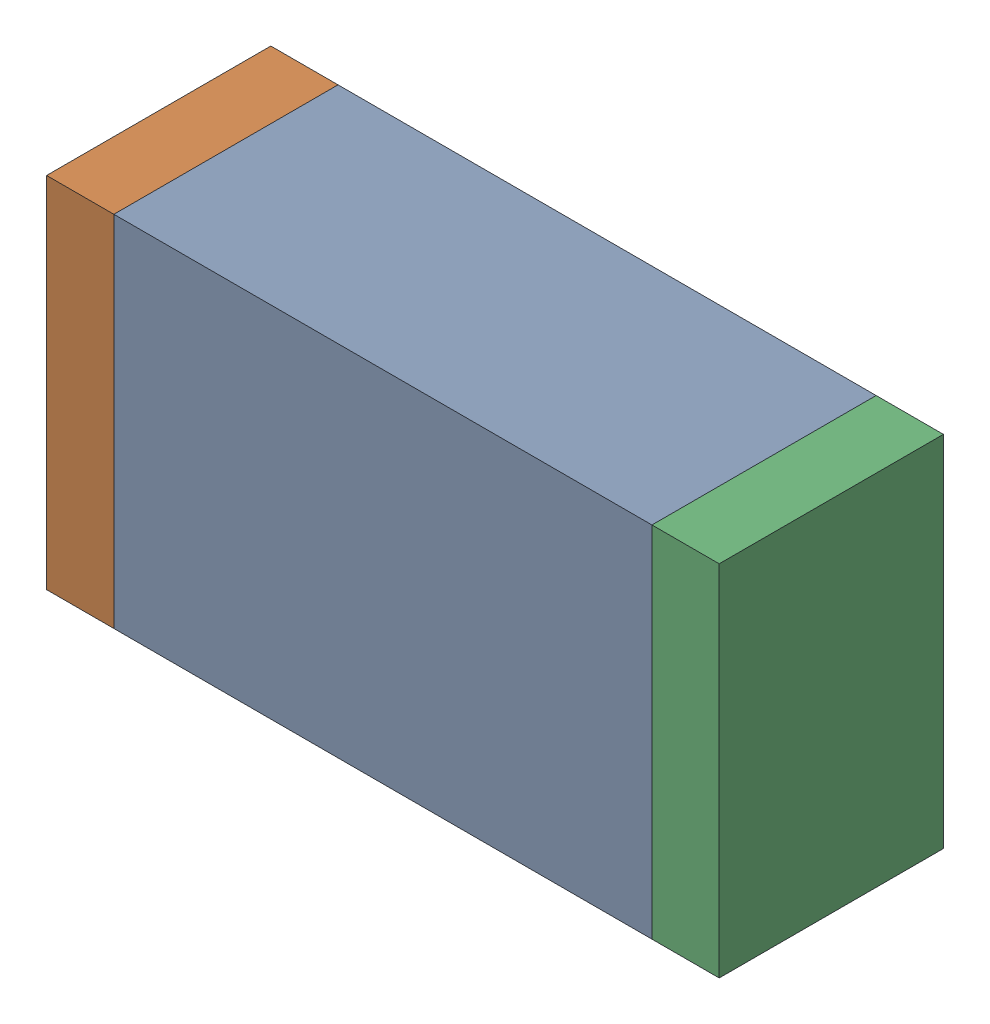
SolidWorks assembly D10, configuration Default. Lengths in mm.
Overall size (1.5 0.8 0.5).
6 component instances, 2 part files, 0 mates.
Components (placement in the parent):
- 836752368-1: 836752368 [Default] at (111.15 18.6 0) size (1.2 0.8 0.5)
  - Extruded-1: Extruded [Default] at origin size (1.2 0.8 0.5)
- 836752496-1: 836752496 [Default] at (110.475 18.6 0) size (0.15 0.8 0.5)
  - Extruded_2-1: Extruded_2 [Default] at origin size (0.15 0.8 0.5)
- 836752496-2: 836752496 [Default] at (111.825 18.6 0) size (0.15 0.8 0.5)
  - Extruded_2-1: Extruded_2 [Default] at origin size (0.15 0.8 0.5)
